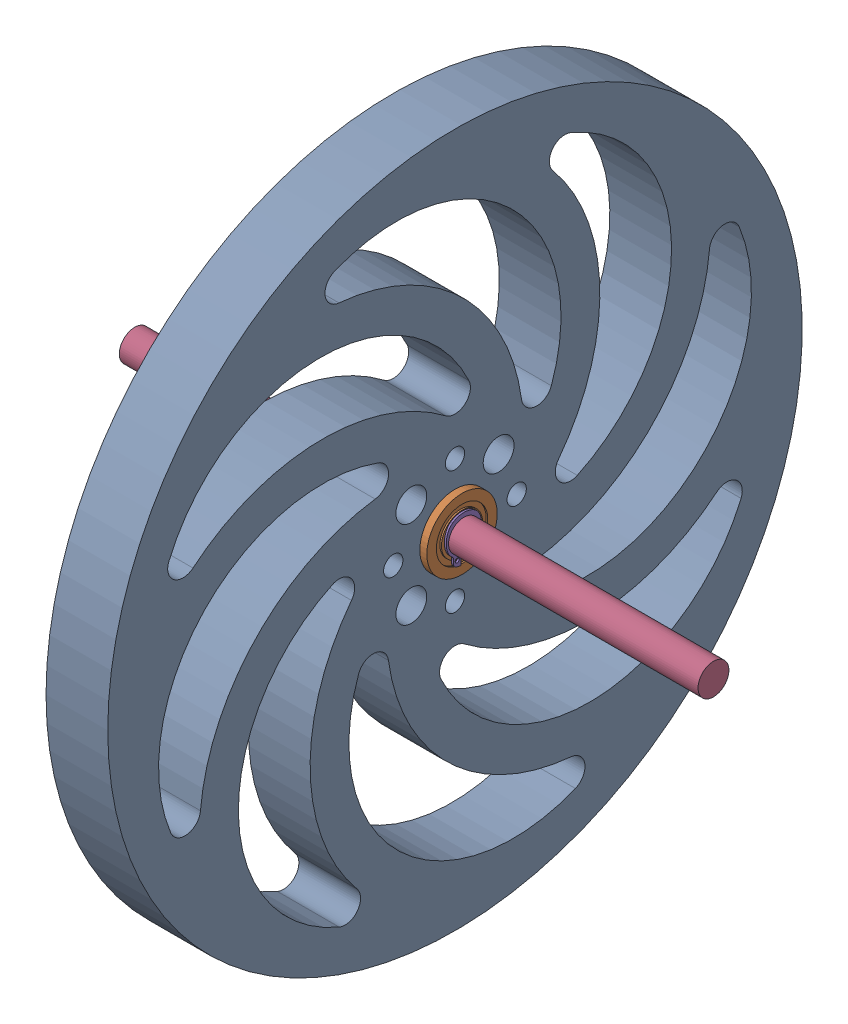
SolidWorks assembly Laser_Sprocket-Passive-Dx, configuration Default. Lengths in mm.
Overall size (75 90 90).
6 component instances, 4 part files, 9 mates.
Components (placement in the parent):
- Laser-Sprocket_Center-Passive-Dx-1: Laser-Sprocket_Center-Passive-Dx [Default] at (26.0533 23.785 -47.0741) size (8 90 90)
- Bearing-4mm-Dx-1: Bearing-4mm-Dx [Default] at (34.9674 23.785 -47.0741) size (3.17 9.12 9.12)
- Bearing-4mm-Dx-2: Bearing-4mm-Dx [Default] at (25.1392 23.785 -47.0741) x (-1 0 0) z (0 0 -1) size (3.17 9.12 9.12)
- Shaft-4mm-Dx-1: Shaft-4mm-Dx [Default] at (-7.4467 23.785 -47.0741) x (1 0 0) z (0 -0.425008 -0.90519) size (75 4 4)
- msh_4-Dx-1: msh_4-Dx [Default] at (35.0923 23.785 -47.0741) x (0 0 1) z (0 1 0) size (4.59 0.25 5.77)
- msh_4-Dx-2: msh_4-Dx [Default] at (25.0143 23.785 -47.0741) x (0 1 0) z (0 0 1) size (4.59 0.25 5.77)
Mates (geometry in assembly coordinates):
- Concentrico1: concentric anti-aligned: circle of Laser-Sprocket_Center-Passive-Dx-1; circle of Bearing-4mm-Dx-2
- Coincidente1: coincident anti-aligned: plane of Laser-Sprocket_Center-Passive-Dx-1 through (26.0533 23.785 -47.0741) normal (-1 0 0); plane of Bearing-4mm-Dx-2 through (26.0533 28.3445 -47.0741) normal (1 0 0)
- Coincidente2: coincident anti-aligned: plane of Laser-Sprocket_Center-Passive-Dx-1 through (34.0533 23.785 -47.0741) normal (1 0 0); plane of Bearing-4mm-Dx-1 through (34.0533 28.3445 -47.0741) normal (-1 0 0)
- Concentrico2: concentric aligned: circle of Laser-Sprocket_Center-Passive-Dx-1; circle of Bearing-4mm-Dx-1
- Concentrico3: concentric anti-aligned: circle of Bearing-4mm-Dx-2; circle of Shaft-4mm-Dx-1
- Coincidente3: coincident anti-aligned: plane of Bearing-4mm-Dx-1 through (34.9673 25.9351 -47.0741) normal (1 0 0); plane of msh_4-Dx-1 through (34.9673 20.6168 -47.5241) normal (-1 0 0)
- Concentrico4: concentric anti-aligned: circle of Bearing-4mm-Dx-1; circle of msh_4-Dx-1
- Concentrico5: concentric aligned: circle of Shaft-4mm-Dx-1; circle of msh_4-Dx-2
- Coincidente4: coincident anti-aligned: plane of Bearing-4mm-Dx-2 through (25.1393 25.9351 -47.0741) normal (-1 0 0); plane of msh_4-Dx-2 through (25.1393 23.335 -50.2423) normal (1 0 0)
